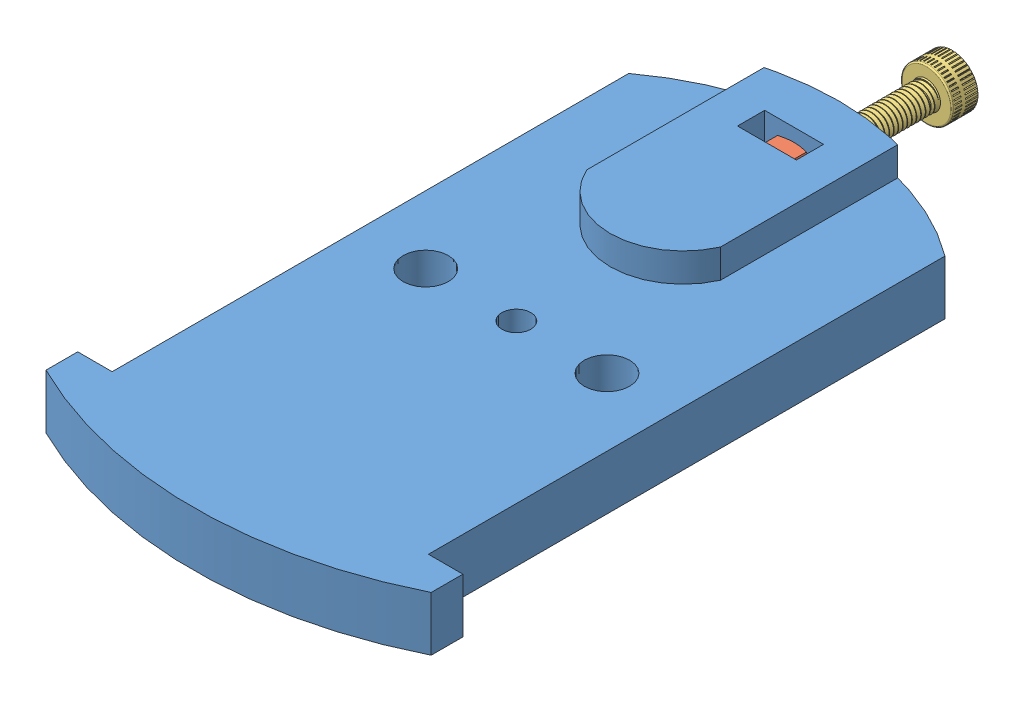
SolidWorks assembly Right Hand Adaptor Assembly, configuration Default. Lengths in mm.
Overall size (42.5 9.18 83.91).
3 component instances, 3 part files, 7 mates.
Components (placement in the parent):
- Right Hand Adaptor Part 2-1: Right Hand Adaptor Part 2 [Default] at origin size (42.5 9.18 71.3)
- 91854A108_Aluminum Hex Nut-1: 91854A108_Aluminum Hex Nut [91854A108] at (0 4.975 -31.6) x (0.866025 0.5 0) z (0 0 1) size (5.5 6.35 2.71)
- 98511A734_Aluminum Socket Head Screw-1: 98511A734_Aluminum Socket Head Screw [98511A734] at (0 4.975 -38.9) x (1 0 0) z (0 0 -1) size (5.68 5.68 23.32)
Mates (geometry in assembly coordinates):
- Coincident1: coincident anti-aligned: plane of Right Hand Adaptor Part 2-1 through (0 6 0) normal (0 1 0); plane of Right Hand Adaptor Part 1-1 through (0 6 0) normal (0 -1 0)
- Coincident2: coincident aligned: circle of Right Hand Adaptor Part 2-1; circle of Right Hand Adaptor Part 1-1
- Coincident3: coincident anti-aligned: plane of Right Hand Adaptor Part 2-1 through (3.25 2.225 -32.8) normal (0 0 1); plane of 91854A108_Aluminum Hex Nut-1 through (-3.1754 4.975 -32.8) normal (0 0 -1)
- Concentric1: concentric anti-aligned: circle of Right Hand Adaptor Part 2-1; circle of 91854A108_Aluminum Hex Nut-1
- Parallel1: parallel aligned: plane of Right Hand Adaptor Part 2-1 through (0 9.175 -20.5657) normal (0 1 0); plane of 91854A108_Aluminum Hex Nut-1 through (1.5877 7.725 -30.4) normal (0 1 0)
- Concentric2: concentric aligned: circle of 91854A108_Aluminum Hex Nut-1; circle of 98511A734_Aluminum Socket Head Screw-1
- Distance1: distance = 17 mm aligned: plane of 98511A734_Aluminum Socket Head Screw-1 through (-2.69 4.975 -47.4) normal (0 0 1); plane of 91854A108_Aluminum Hex Nut-1 through (-3.1754 4.975 -30.4) normal (0 0 1)
